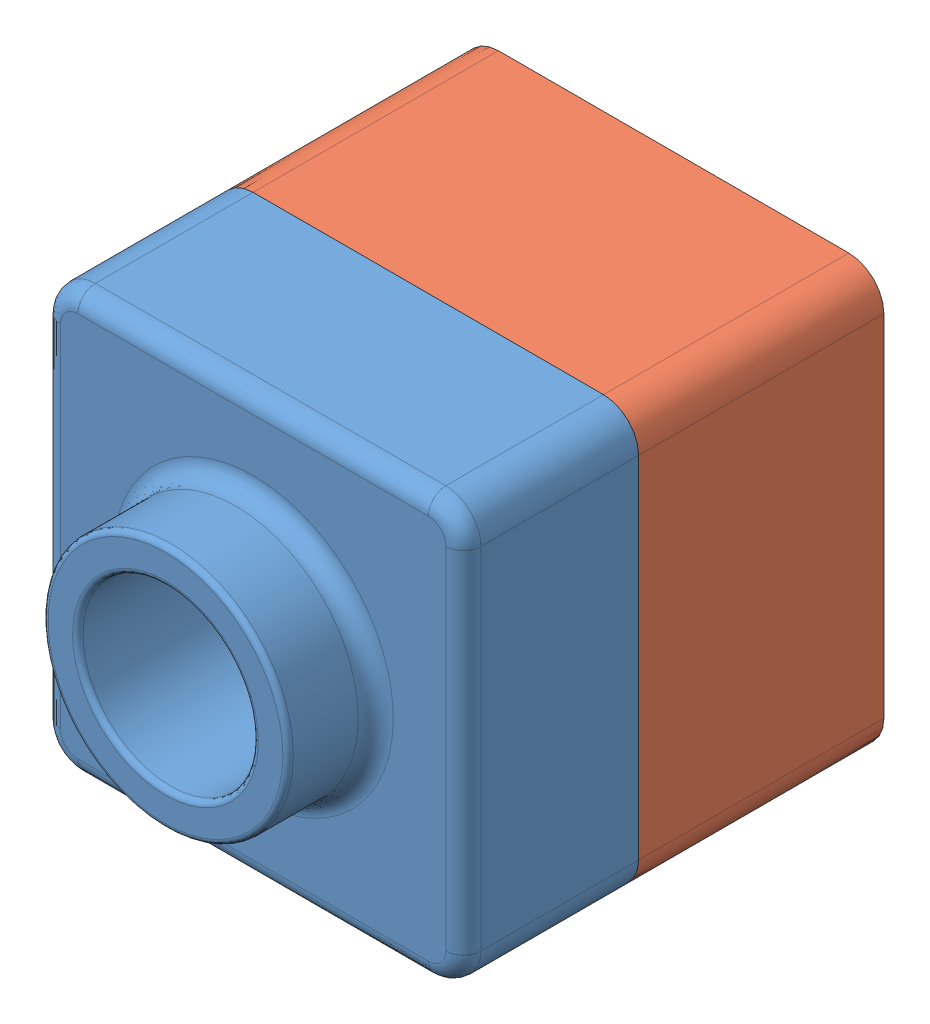
SolidWorks assembly tutor, configuration Default. Lengths in mm.
Overall size (120 120 145).
2 component instances, 2 part files, 3 mates.
Components (placement in the parent):
- Tutor1-1: Tutor1 [Default] at (1.5981 22.2724 142.3168) size (120 120 75)
- Tutor2-1: Tutor2 [Default] at (1.5981 22.2724 72.3168) size (120 120 90)
Mates (geometry in assembly coordinates):
- Coincident2: coincident: line of Tutor1-1 through (111.5981 142.2724 142.3168) axis (-1 0 0); line of Tutor2-1 through (111.5981 142.2724 142.3168) axis (-1 0 0)
- Coincident3: coincident: plane of Tutor1-1 through (121.5981 22.2724 192.3168) normal (1 0 0); plane of Tutor2-1 through (121.5981 22.2724 162.3168) normal (1 0 0)
- Coincident4: coincident aligned: plane of Tutor1-1 through (1.5981 142.2724 192.3168) normal (0 1 0); plane of Tutor2-1 through (1.5981 142.2724 162.3168) normal (0 1 0)
